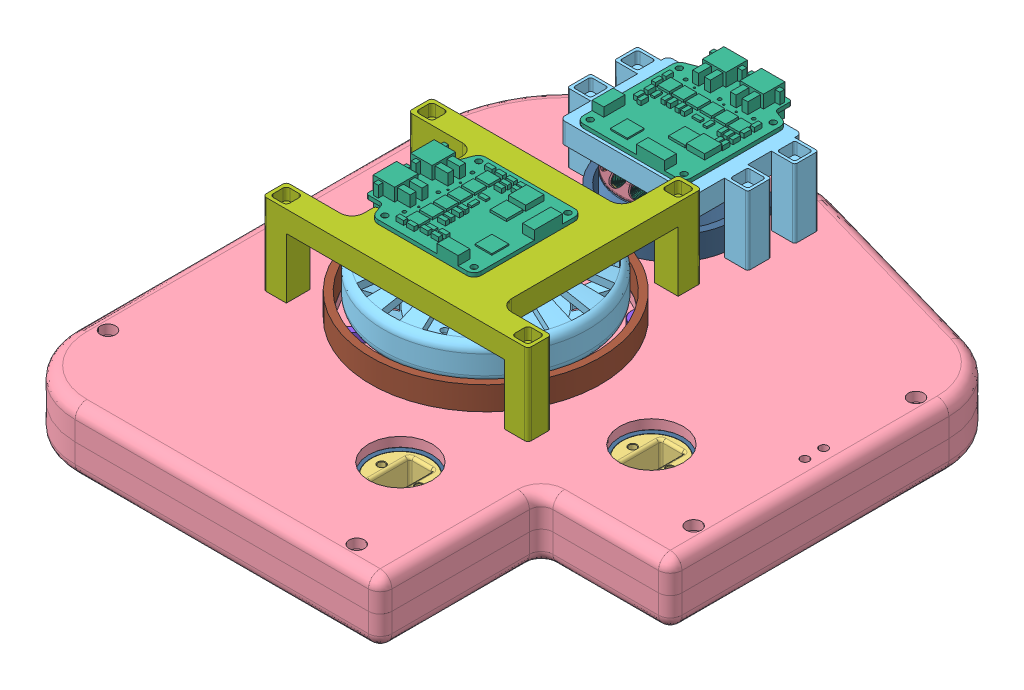
SolidWorks assembly Large Small Motor System, configuration Default. Lengths in mm.
Overall size (215 68.35 240).
128 component instances, 29 part files, 38 mates.
Components (placement in the parent):
- Large_Motor_Pulley_System_Output-1: Large_Motor_Pulley_System_Output [Default] x (1 0 0) z (0 0 -1) size (143.04 56.2 156.68)
  - Small_Pulley_Large_Pulley-1: Small_Pulley_Large_Pulley [Default] at (-35 -6.3 -71.381) x (0 0 -1) z (0 -1 0) size (60 60 20.5)
    - transmission_pulley_at3_t60_center-1: transmission_pulley_at3_t60_center [Standard] at origin size (60 60 7.63)
    - transmission_pulley_at3_t10_motor_no_hub-1: transmission_pulley_at3_t10_motor_no_hub [Standard] x (0.135506 0.990777 0) z (-0.990777 0.135506 0) size (9.14 20.5 8.82)
  - transmission_pulley_at3_t60_output-1: transmission_pulley_at3_t60_output [Standard] at (35 2.35 -71.381) x (-1 0 0) z (0 -1 0) size (56.43 56.43 18.7)
  - Timing Belt-2: Timing Belt [Default] at (-35 4.7 -71.381) size (108.94 4 62.48)
  - Shaft_Small_Pulley_Large_Motor-1: Shaft_Small_Pulley_Large_Motor [Default] at (0 -25.25 0) size (87 54.2 87)
    - Large_Motor-1: Large_Motor [Default] at origin size (87 30.6 87)
    - Shaft_Flange_Small_Pulley_For_Large_Motor-1: Shaft_Flange_Small_Pulley_For_Large_Motor [Default] at (0 17.25 0) size (35 23.7 35)
    - transmission_pulley_at3_t10_motor-1: transmission_pulley_at3_t10_motor [Standard] at (0 18.55 0) x (0 0 -1) z (1 0 0) size (9.14 6.7 8.82)
  - Timing Belt 79.5 mm-1: Timing Belt 79.5 mm [Default] at (0 -2 0) x (-0.440252 0 -0.897874) z (0.897874 0 -0.440252) size (118.44 4 62.48)
  - Bearing 4x8x2-1: Bearing 4x8x2 [Default] at (-35 10.7 -71.381) size (8 2 8)
  - Bearing 4x8x2-2: Bearing 4x8x2 [Default] at (-35 -7.8 -71.381) x (0.837169 0 0.546944) z (0.546944 0 -0.837169) size (8 2 8)
  - Bearing 32x25x4-1: Bearing 32x25x4 [Default] at (35 -7 -71.381) size (32 4 32)
  - Bearing 32x25x4-2: Bearing 32x25x4 [Default] at (35 8.7 -71.381) x (0.999549 0 0.030039) z (-0.030039 0 0.999549) size (32 4 32)
- Small_Motor_Pulley_System_Output-1: Small_Motor_Pulley_System_Output [Default] at (0 0 -79.5) x (0 0 1) z (1 0 0) size (160.41 47.51 149.9)
  - Shaft_Small_Pulley_Small_Motor-1: Shaft_Small_Pulley_Small_Motor [Default] at (24.2764 -22.45 79.8349) x (0.290929 0 0.956745) z (-0.956745 0 0.290929) size (65.46 46.51 65.46)
    - transmission_pulley_at3_t10_motor-1: transmission_pulley_at3_t10_motor [Standard] at (-83.4443 15.75 0) x (0.956745 0 0.290929) z (-0.290929 0 0.956745) size (9.14 6.7 8.82)
    - Shaft_Flange_Small_Pulley-1: Shaft_Flange_Small_Pulley [Default] at (-83.4443 14.25 0) x (-0.290929 0 0.956745) z (-0.956745 0 -0.290929) size (24 24.9 24)
    - Tarot 4008 Motor Assembly-1: Tarot 4008 Motor Assembly [Default] at (-83.4443 0 0) size (65.46 21.61 65.46)
      - Tarot 4008 Motor Assembly.STEP-1: Tarot 4008 Motor Assembly.STEP [Default] at origin size (65.46 21.61 65.46)
        - Stator Assembly.STEP-1: Stator Assembly.STEP [Default] at origin size (63.83 17.11 63.8)
          - Iron Core.STEP-1: Iron Core.STEP [Default] at origin size (38.93 8.01 39)
          - Stator Base Plate.STEP-1: Stator Base Plate.STEP [Default] at (0 -9.75 0) x (0.733167 0 -0.680048) z (0.680048 0 0.733167) size (52.76 13.79 44.5)
          - Bearing.STEP-1: Bearing.STEP [Default] at (0 2 0) x (0.876835 0 0.480792) z (0 -1 0) size (12 12 4)
          - Bearing.STEP-2: Bearing.STEP [Default] at (0 -7.75 0) x (1 0 0) z (0 1 0) size (12 12 4)
          - Motor Windings.STEP-1: Motor Windings.STEP [Default] at (-16.4024 0 9.47) x (0.5 0 0.866025) z (-0.866025 0 0.5) size (3.5 9.5 9)
          - Motor Windings.STEP-2: Motor Windings.STEP [Default] at (-12.1743 0 14.5088) x (-0.766044 0 -0.642788) z (-0.642788 0 0.766044) size (3.5 9.5 9)
          - Motor Windings.STEP-3: Motor Windings.STEP [Default] at (-6.4778 0 17.7977) x (-0.939693 0 -0.34202) z (-0.34202 0 0.939693) size (3.5 9.5 9)
          - Motor Windings.STEP-4: Motor Windings.STEP [Default] at (0 0 18.9399) size (3.5 9.5 9)
          - Motor Windings.STEP-5: Motor Windings.STEP [Default] at (6.4778 0 17.7977) x (0.939693 0 -0.34202) z (0.34202 0 0.939693) size (3.5 9.5 9)
          - Motor Windings.STEP-6: Motor Windings.STEP [Default] at (12.1743 0 14.5088) x (0.766044 0 -0.642788) z (0.642788 0 0.766044) size (3.5 9.5 9)
          - Motor Windings.STEP-7: Motor Windings.STEP [Default] at (16.4024 0 9.47) x (0.5 0 -0.866025) z (0.866025 0 0.5) size (3.5 9.5 9)
          - Motor Windings.STEP-8: Motor Windings.STEP [Default] at (18.6522 0 3.2889) x (0.173648 0 -0.984808) z (0.984808 0 0.173648) size (3.5 9.5 9)
          - Motor Windings.STEP-9: Motor Windings.STEP [Default] at (18.6522 0 -3.2889) x (-0.173648 0 -0.984808) z (0.984808 0 -0.173648) size (3.5 9.5 9)
          - Motor Windings.STEP-10: Motor Windings.STEP [Default] at (16.4024 0 -9.47) x (0.5 0 0.866025) z (0.866025 0 -0.5) size (3.5 9.5 9)
          - Motor Windings.STEP-11: Motor Windings.STEP [Default] at (0 0 -18.9399) x (1 0 0) z (0 0 -1) size (3.5 9.5 9)
          - Motor Windings.STEP-12: Motor Windings.STEP [Default] at (-6.4778 0 -17.7977) x (0.939693 0 -0.34202) z (-0.34202 0 -0.939693) size (3.5 9.5 9)
          - Motor Windings.STEP-13: Motor Windings.STEP [Default] at (-12.1743 0 -14.5088) x (0.766044 0 -0.642788) z (-0.642788 0 -0.766044) size (3.5 9.5 9)
          - Motor Windings.STEP-14: Motor Windings.STEP [Default] at (-16.4024 0 -9.47) x (0.5 0 -0.866025) z (-0.866025 0 -0.5) size (3.5 9.5 9)
          - Motor Windings.STEP-15: Motor Windings.STEP [Default] at (-18.6522 0 -3.2889) x (-0.173648 0 0.984808) z (-0.984808 0 -0.173648) size (3.5 9.5 9)
          - Motor Windings.STEP-16: Motor Windings.STEP [Default] at (-18.6522 0 3.2889) x (0.173648 0 0.984808) z (-0.984808 0 0.173648) size (3.5 9.5 9)
          - Motor Windings.STEP-17: Motor Windings.STEP [Default] at (6.7116 0 -7.9986) x (0.766044 0 0.642788) z (-0.642788 0 0.766044) size (3.5 9.5 9)
          - Motor Windings.STEP-18: Motor Windings.STEP [Default] at (3.5712 0 -9.8118) x (0.939693 0 0.34202) z (-0.34202 0 0.939693) size (3.5 9.5 9)
          - Retaining Washer.STEP-1: Retaining Washer.STEP [Default] at (0 -11.75 0) x (0.999968 0 -0.008017) z (0.008017 0 0.999968) size (9.07 2.5 9.07)
          - M3x0.5mm-5mm Button Head Screw_91239A110.STEP-1: M3x0.5mm-5mm Button Head Screw_91239A110.STEP [Default] at (0 -12.35 0) x (0.201004 0 -0.97959) z (0 -1 0) size (5.7 5.7 6.66)
        - Rotor Assembly.STEP-1: Rotor Assembly.STEP [Default] at (40.392 -17.2195 -15.1118) x (-0.078978 0 0.996876) z (-0.996876 0 -0.078978) size (62.36 18.01 62.36)
          - Rotor Plate.STEP-1: Rotor Plate.STEP [Default] at (18.2547 23.4695 39.0723) size (44.5 18.01 44.5)
          - Rotor Ring.STEP-1: Rotor Ring.STEP [Default] at (18.2547 12.4695 39.0723) x (0.796025 0 0.605264) z (0 1 0) size (44.5 44.5 9.8)
          - Magnet.STEP-1: Magnet.STEP [Default] at (23.6782 17.4695 18.8316) x (0.965926 0 0.258819) z (-0.258819 0 0.965926) size (4 8 1.5)
          - Magnet.STEP-2: Magnet.STEP [Default] at (18.2547 17.4695 18.1176) size (4 8 1.5)
          - Magnet.STEP-3: Magnet.STEP [Default] at (12.8312 17.4695 18.8316) x (0.965926 0 -0.258819) z (0.258819 0 0.965926) size (4 8 1.5)
          - Magnet.STEP-4: Magnet.STEP [Default] at (7.7773 17.4695 20.925) x (0.866025 0 -0.5) z (0.5 0 0.866025) size (4 8 1.5)
          - Magnet.STEP-5: Magnet.STEP [Default] at (3.4374 17.4695 24.2551) x (0.707107 0 -0.707107) z (0.707107 0 0.707107) size (4 8 1.5)
          - Magnet.STEP-6: Magnet.STEP [Default] at (0.1073 17.4695 28.5949) x (0.5 0 -0.866025) z (0.866025 0 0.5) size (4 8 1.5)
          - Magnet.STEP-7: Magnet.STEP [Default] at (-1.9861 17.4695 33.6488) x (0.258819 0 -0.965926) z (0.965926 0 0.258819) size (4 8 1.5)
          - Magnet.STEP-8: Magnet.STEP [Default] at (-2.7001 17.4695 39.0723) x (0 0 -1) z (1 0 0) size (4 8 1.5)
          - Magnet.STEP-9: Magnet.STEP [Default] at (-1.9861 17.4695 44.4958) x (-0.258819 0 -0.965926) z (0.965926 0 -0.258819) size (4 8 1.5)
          - Magnet.STEP-10: Magnet.STEP [Default] at (0.1073 17.4695 49.5497) x (-0.5 0 -0.866025) z (0.866025 0 -0.5) size (4 8 1.5)
          - Magnet.STEP-11: Magnet.STEP [Default] at (3.4374 17.4695 53.8896) x (-0.707107 0 -0.707107) z (0.707107 0 -0.707107) size (4 8 1.5)
          - Magnet.STEP-12: Magnet.STEP [Default] at (7.7773 17.4695 57.2197) x (-0.866025 0 -0.5) z (0.5 0 -0.866025) size (4 8 1.5)
          - Magnet.STEP-13: Magnet.STEP [Default] at (12.8312 17.4695 59.3131) x (-0.965926 0 -0.258819) z (0.258819 0 -0.965926) size (4 8 1.5)
          - Magnet.STEP-14: Magnet.STEP [Default] at (18.2547 17.4695 60.0271) x (-1 0 0) z (0 0 -1) size (4 8 1.5)
          - Magnet.STEP-15: Magnet.STEP [Default] at (23.6782 17.4695 59.3131) x (-0.965926 0 0.258819) z (-0.258819 0 -0.965926) size (4 8 1.5)
          - Magnet.STEP-16: Magnet.STEP [Default] at (28.7321 17.4695 57.2197) x (-0.866025 0 0.5) z (-0.5 0 -0.866025) size (4 8 1.5)
          - Magnet.STEP-17: Magnet.STEP [Default] at (33.072 17.4695 53.8896) x (-0.707107 0 0.707107) z (-0.707107 0 -0.707107) size (4 8 1.5)
          - Magnet.STEP-18: Magnet.STEP [Default] at (36.4021 17.4695 49.5497) x (-0.5 0 0.866025) z (-0.866025 0 -0.5) size (4 8 1.5)
          - Magnet.STEP-19: Magnet.STEP [Default] at (38.4955 17.4695 44.4958) x (-0.258819 0 0.965926) z (-0.965926 0 -0.258819) size (4 8 1.5)
          - Magnet.STEP-20: Magnet.STEP [Default] at (39.2095 17.4695 39.0723) x (0 0 1) z (-1 0 0) size (4 8 1.5)
          - Magnet.STEP-21: Magnet.STEP [Default] at (38.4955 17.4695 33.6488) x (0.258819 0 0.965926) z (-0.965926 0 0.258819) size (4 8 1.5)
          - Magnet.STEP-22: Magnet.STEP [Default] at (36.4021 17.4695 28.5949) x (0.5 0 0.866025) z (-0.866025 0 0.5) size (4 8 1.5)
          - Magnet.STEP-23: Magnet.STEP [Default] at (33.072 17.4695 24.2551) x (0.707107 0 0.707107) z (-0.707107 0 0.707107) size (4 8 1.5)
          - Magnet.STEP-24: Magnet.STEP [Default] at (28.7321 17.4695 20.925) x (0.866025 0 0.5) z (-0.5 0 0.866025) size (4 8 1.5)
    - hexalobular socket pan head_iso-1: hexalobular socket pan head_iso [ISO 14583 - M3 x 5 x 4 - 4.8-C] at (-81.2491 7.25 -5.6037) size (5.6 7.4 5.6)
    - hexalobular socket pan head_iso-2: hexalobular socket pan head_iso [ISO 14583 - M3 x 5 x 4 - 4.8-C] at (-88.1146 7.25 -1.8278) size (5.6 7.4 5.6)
    - hexalobular socket pan head_iso-3: hexalobular socket pan head_iso [ISO 14583 - M3 x 5 x 4 - 4.8-C] at (-78.7741 7.25 1.8278) size (5.6 7.4 5.6)
    - hexalobular socket pan head_iso-4: hexalobular socket pan head_iso [ISO 14583 - M3 x 5 x 4 - 4.8-C] at (-85.6396 7.25 5.6037) x (0.982493 0 0.186302) z (-0.186302 0 0.982493) size (5.6 7.4 5.6)
  - Small_Pulley_Large_Pulley-1: Small_Pulley_Large_Pulley [Default] at (22.681 -6.3 66.2237) x (-0.888904 0 -0.458093) z (0 -1 0) size (60 60 20.5)
    - transmission_pulley_at3_t60_center-1: transmission_pulley_at3_t60_center [Standard] at origin size (60 60 7.63)
    - transmission_pulley_at3_t10_motor_no_hub-1: transmission_pulley_at3_t10_motor_no_hub [Standard] x (0.135506 0.990777 0) z (-0.990777 0.135506 0) size (9.14 20.5 8.82)
  - Timing Belt-1: Timing Belt [Default] at (0 -2 0) x (0.324014 0 0.946052) z (-0.946052 0 0.324014) size (108.94 4 62.48)
  - transmission_pulley_at3_t60_output-1: transmission_pulley_at3_t60_output [Standard] at (90.88 2.35 82) x (0 0 -1) z (0 -1 0) size (56.43 56.43 18.7)
  - Timing Belt-2: Timing Belt [Default] at (22.681 4.7 66.2237) x (0.974272 0 0.225376) z (-0.225376 0 0.974272) size (108.94 4 62.48)
  - Bearing 4x8x2-1: Bearing 4x8x2 [Default] at (22.681 -9.8 66.2237) size (8 2 8)
  - Bearing 4x8x2-2: Bearing 4x8x2 [Default] at (22.681 10.7 66.2237) size (8 2 8)
  - Bearing 32x25x4-1: Bearing 32x25x4 [Default] at (90.88 -7 82) size (32 4 32)
  - Bearing 32x25x4-2: Bearing 32x25x4 [Default] at (90.88 8.7 82) x (0.999508 0 -0.031368) z (0.031368 0 0.999508) size (32 4 32)
- Outer Case-1: Outer Case [Default] at (25 -14.7 120) size (215 26.5 240)
- Bridge For Small Motor-1: Bridge For Small Motor [Default] at (0 32.2 -79.189) x (0 0 1) z (-1 0 0) size (46 29.3 77)
- Motor Controller-1: Motor Controller [Default] at (0 41.1 -71.5) x (-1 0 0) z (0 0 -1) size (46 13.35 53)
- Motor Controller-2: Motor Controller [Default] at (8 46.5 0) x (0 0 1) z (-1 0 0) size (46 13.35 53)
- Large Motor Bridge-1: Large Motor Bridge [Default] at (0 37.5 0) size (113 34.7 96)
- Roller And 4x8x2 Bearing-1: Roller And 4x8x2 Bearing [Default] at (99.441 -5.2 -28.5801) size (11.31 4 11.31)
  - Tranmisison Belt Roller-1: Tranmisison Belt Roller [Standard] at origin size (11.2 3 11.2)
  - Bearing 4x8x2-1: Bearing 4x8x2 [Default] at (0 -1.5 0) size (8 2 8)
  - Nut-1: Nut [Default] at (0 -2.5 0) x (-0.734276 0 0.678851) z (-0.678851 0 -0.734276) size (8 1 8)
- Roller And 4x8x2 Bearing-2: Roller And 4x8x2 Bearing [Default] at (48.7794 -5.2 -16.8581) size (11.31 4 11.31)
  - Tranmisison Belt Roller-1: Tranmisison Belt Roller [Standard] at origin size (11.2 3 11.2)
  - Bearing 4x8x2-1: Bearing 4x8x2 [Default] at (0 -1.5 0) size (8 2 8)
  - Nut-1: Nut [Default] at (0 -2.5 0) x (-0.734276 0 0.678851) z (-0.678851 0 -0.734276) size (8 1 8)
- Small Ring-1: Small Ring [Default] at (0 11.8 -79.5) x (0.671647 0 -0.740871) z (0.740871 0 0.671647) size (72 10 54) (hidden)
- Large Ring-1: Large Ring [Default] at (0 11.8 0) x (-0.850753 0 -0.525566) z (0.525566 0 -0.850753) size (118 10 98) (hidden)
- Roller And 4x8x2 Bearing-3: Roller And 4x8x2 Bearing [Default] at (0 -5.2 45.38) size (11.31 4 11.31)
  - Tranmisison Belt Roller-1: Tranmisison Belt Roller [Standard] at origin size (11.2 3 11.2)
  - Bearing 4x8x2-1: Bearing 4x8x2 [Default] at (0 -1.5 0) size (8 2 8)
  - Nut-1: Nut [Default] at (0 -2.5 0) x (-0.734276 0 0.678851) z (-0.678851 0 -0.734276) size (8 1 8)
- Roller And 4x8x2 Bearing-4: Roller And 4x8x2 Bearing [Default] at (0 -5.2 97.38) x (0.997468 0 0.071117) z (-0.071117 0 0.997468) size (11.31 4 11.31)
  - Tranmisison Belt Roller-1: Tranmisison Belt Roller [Standard] at origin size (11.2 3 11.2)
  - Bearing 4x8x2-1: Bearing 4x8x2 [Default] at (0 -1.5 0) size (8 2 8)
  - Nut-1: Nut [Default] at (0 -2.5 0) x (-0.734276 0 0.678851) z (-0.678851 0 -0.734276) size (8 1 8)
- Roller And 4x8x2 Bearing-5: Roller And 4x8x2 Bearing [Default] at (24.5217 1.05 -43.0903) size (11.31 4 11.31)
  - Tranmisison Belt Roller-1: Tranmisison Belt Roller [Standard] at origin size (11.2 3 11.2)
  - Bearing 4x8x2-1: Bearing 4x8x2 [Default] at (0 -1.5 0) size (8 2 8)
  - Nut-1: Nut [Default] at (0 -2.5 0) x (-0.734276 0 0.678851) z (-0.678851 0 -0.734276) size (8 1 8)
- Roller And 4x8x2 Bearing-6: Roller And 4x8x2 Bearing [Default] at (41.6947 1.05 -93.231) size (11.31 4 11.31)
  - Tranmisison Belt Roller-1: Tranmisison Belt Roller [Standard] at origin size (11.2 3 11.2)
  - Bearing 4x8x2-1: Bearing 4x8x2 [Default] at (0 -1.5 0) size (8 2 8)
  - Nut-1: Nut [Default] at (0 -2.5 0) x (-0.734276 0 0.678851) z (-0.678851 0 -0.734276) size (8 1 8)
- Roller And 4x8x2 Bearing-7: Roller And 4x8x2 Bearing [Default] at (-43.3846 1.05 28.2877) size (11.31 4 11.31)
  - Tranmisison Belt Roller-1: Tranmisison Belt Roller [Standard] at origin size (11.2 3 11.2)
  - Bearing 4x8x2-1: Bearing 4x8x2 [Default] at (0 -1.5 0) size (8 2 8)
  - Nut-1: Nut [Default] at (0 -2.5 0) x (-0.734276 0 0.678851) z (-0.678851 0 -0.734276) size (8 1 8)
- Roller And 4x8x2 Bearing-8: Roller And 4x8x2 Bearing [Default] at (7.6465 1.05 34.3763) size (11.31 4 11.31)
  - Tranmisison Belt Roller-1: Tranmisison Belt Roller [Standard] at origin size (11.2 3 11.2)
  - Bearing 4x8x2-1: Bearing 4x8x2 [Default] at (0 -1.5 0) size (8 2 8)
  - Nut-1: Nut [Default] at (0 -2.5 0) x (-0.734276 0 0.678851) z (-0.678851 0 -0.734276) size (8 1 8)
- Bearing 4x8x2-1: Bearing 4x8x2 [Default] at (0 -12.7 -79.5) size (8 2 8)
- Bearing 4x8x2-2: Bearing 4x8x2 [Default] at (0 -12.7 0) size (8 2 8)
Mates (geometry in assembly coordinates):
- Coincident1: coincident aligned: plane of assembly through (0 0 0) normal (1 0 0); plane of Large_Motor_Pulley_System_Output-1 through (0 0 0) normal (1 0 0)
- Distance1: distance = 0 mm anti-aligned: plane of Large_Motor_Pulley_System_Output-1 through (0 0 0) normal (0 -1 0)
- Coincident3: coincident anti-aligned: plane of Large_Motor_Pulley_System_Output-1 through (0 0 0) normal (0 0 -1)
- Distance2: distance = 79.5 mm aligned: plane of Small_Motor_Pulley_System_Output-1 through (0 0 -79.5) normal (0 0 1)
- Coincident6: coincident anti-aligned: plane of Small_Motor_Pulley_System_Output-1 through (0 0 -79.5) normal (0 -1 0)
- Coincident9: coincident aligned: plane of Small_Motor_Pulley_System_Output-1 through (0 0 -79.5) normal (1 0 0)
- Distance3: distance = 25 mm aligned: plane of Outer Case-1 through (25 -14.7 120) normal (1 0 0)
- Distance4: distance = 120 mm aligned: plane of Outer Case-1 through (25 -14.7 120) normal (0 0 1)
- Coincident10: coincident anti-aligned: plane of Large_Motor_Pulley_System_Output-1/Bearing 4x8x2-2 through (-35 9.8 71.381) normal (0 1 0); plane of Outer Case-1 through (-35 9.8 71.38) normal (0 -1 0)
- Parallel1: parallel aligned: plane of Bridge For Small Motor-1 through (0 32.2 -79.189) normal (0 0 1)
- Distance6: distance = 7.5 mm anti-aligned: plane of Motor Controller-1 through (0 39.7 -79.5) normal (0 -1 0); plane of Small_Motor_Pulley_System_Output-1/Shaft_Small_Pulley_Small_Motor-1/Tarot 4008 Motor Assembly-1/Tarot 4008 Motor Assembly.STEP-1/Stator Assembly.STEP-1/Stator Base Plate.STEP-1 through (0 32.2 -79.5) normal (0 1 0)
- Distance7: distance = 9 mm anti-aligned: plane of Motor Controller-2 through (-8.5 46.5 0) normal (0 -1 0); plane of Large_Motor_Pulley_System_Output-1/Shaft_Small_Pulley_Large_Motor-1/Large_Motor-1 through (26 37.5 0) normal (0 1 0)
- Coincident11: coincident anti-aligned: plane of Motor Controller-1 through (0 41.1 -71.5) normal (-1 0 0)
- Distance8: distance = 71.5 mm: plane of assembly through (0 0 0) normal (0 0 1); plane of assembly; plane of Motor Controller-1 through (0 41.1 -71.5) normal (0 0 -1)
- Coincident12: coincident anti-aligned: plane of Small_Motor_Pulley_System_Output-1/Shaft_Small_Pulley_Small_Motor-1/Tarot 4008 Motor Assembly-1/Tarot 4008 Motor Assembly.STEP-1/Stator Assembly.STEP-1/Stator Base Plate.STEP-1 through (0 32.2 -79.5) normal (0 1 0); plane of Bridge For Small Motor-1 through (-26.5 32.2 -104.189) normal (0 -1 0)
- Coincident13: coincident anti-aligned: plane of Bridge For Small Motor-1 through (0 32.2 -79.189) normal (-1 0 0)
- Perpendicular1: perpendicular: plane of Motor Controller-2 through (8 46.5 0) normal (0 0 1)
- Distance9: distance = 8 mm: plane of assembly through (0 0 0) normal (1 0 0); plane of assembly; plane of Motor Controller-2 through (8 46.5 0) normal (-1 0 0)
- Coincident16: coincident aligned: plane of Motor Controller-2 through (8 46.5 0) normal (0 0 1)
- Coincident17: coincident aligned: circle of Large_Motor_Pulley_System_Output-1/Shaft_Small_Pulley_Large_Motor-1/Large_Motor-1; circle of Large Motor Bridge-1
- Coincident19: coincident aligned: plane of Large Motor Bridge-1 through (0 37.5 0) normal (1 0 0)
- Coincident20: coincident: circle of Outer Case-1; circle of Roller And 4x8x2 Bearing-1/Nut-1
- Coincident21: coincident: circle of Outer Case-1; circle of Roller And 4x8x2 Bearing-2/Nut-1
- Coincident22: coincident aligned: plane of Outer Case-1 through (25 11.8 120) normal (0 1 0); plane of Small Ring-1 through (0 11.8 -79.5) normal (0 1 0)
- Concentric1: concentric aligned: circle of Outer Case-1; circle of Small Ring-1
- Lock1: lock: unknown of Outer Case-1; unknown of Small Ring-1
- Concentric2: concentric aligned: circle of Outer Case-1; circle of Large Ring-1
- Coincident26: coincident anti-aligned: plane of Outer Case-1 through (25 11.8 120) normal (0 1 0); plane of Large Ring-1 through (0 11.8 0) normal (0 -1 0)
- Coincident29: coincident aligned: circle of Outer Case-1; circle of Roller And 4x8x2 Bearing-3/Nut-1
- Coincident30: coincident aligned: circle of Outer Case-1; circle of Roller And 4x8x2 Bearing-4/Nut-1
- Coincident31: coincident aligned: circle of Outer Case-1; circle of Roller And 4x8x2 Bearing-6/Nut-1
- Coincident32: coincident aligned: circle of Outer Case-1; circle of Roller And 4x8x2 Bearing-5/Nut-1
- Coincident33: coincident aligned: circle of Outer Case-1; circle of Roller And 4x8x2 Bearing-7/Nut-1
- Coincident34: coincident aligned: circle of Outer Case-1; circle of Roller And 4x8x2 Bearing-8/Nut-1
- Coincident35: coincident anti-aligned: plane of Outer Case-1 through (0 -12.7 -79.5) normal (0 1 0); plane of Bearing 4x8x2-1 through (0 -12.7 -79.5) normal (0 -1 0)
- Concentric3: concentric aligned: circle of Outer Case-1; circle of Bearing 4x8x2-1
- Coincident36: coincident anti-aligned: plane of Outer Case-1 through (0 -12.7 0) normal (0 1 0); plane of Bearing 4x8x2-2 through (0 -12.7 0) normal (0 -1 0)
- Concentric4: concentric aligned: circle of Outer Case-1; circle of Bearing 4x8x2-2
